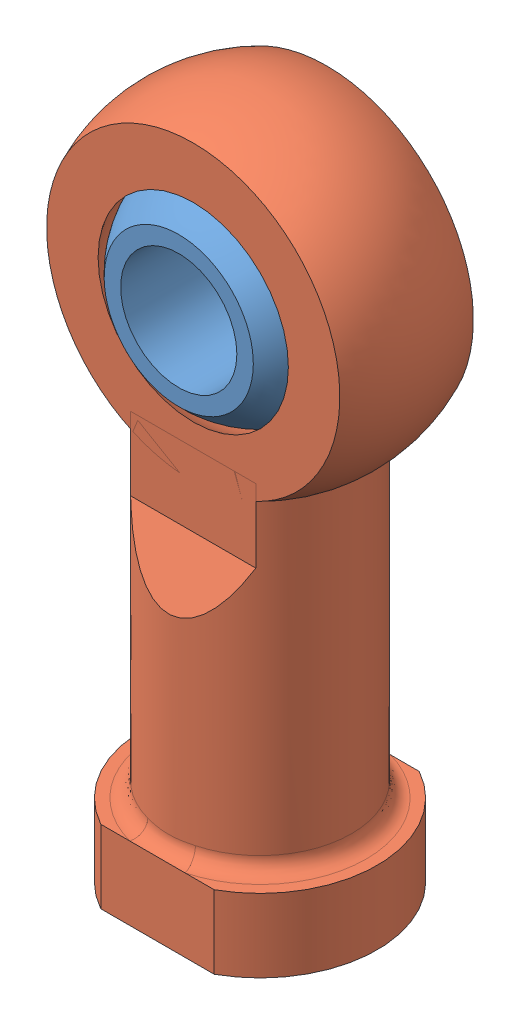
SolidWorks assembly RodEnd312Fem, configuration Default. Lengths in mm.
Overall size (22 47 22.2).
2 component instances, 2 part files, 1 mates.
Components (placement in the parent):
- RodEndBall312-1: RodEndBall312 [Default] at origin size (15.06 15.06 22.2)
- RodEndRace312Fem-1: RodEndRace312Fem [Default] at origin size (22 47 14)
Mates (geometry in assembly coordinates):
- Concentric1: concentric: sphere of ?; unknown of ?
